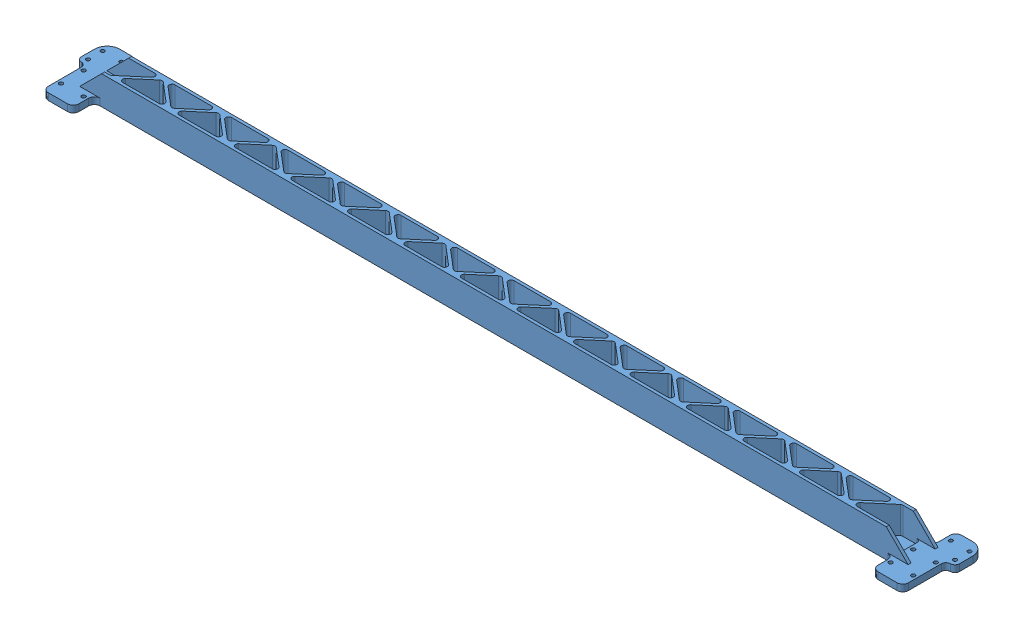
SolidWorks assembly crossbar-700-10, configuration Aluminum Crossbar. Lengths in mm.
Overall size (777 25.4 65).
5 component instances, 2 part files, 8 mates.
Components (placement in the parent):
- m4_composite_insert_93918A102-1: m4_composite_insert_93918A102 [93918A102] at (-74.929 387.0105 24.0665) x (-0.969139 0 0.246516) z (-0.246516 0 -0.969139) (suppressed, hidden)
- m4_composite_insert_93918A102-2: m4_composite_insert_93918A102 [93918A102] at (-91.429 387.0105 36.8915) x (-0.293941 0 0.955824) z (-0.955824 0 -0.293941) (suppressed, hidden)
- m4_composite_insert_93918A102-3: m4_composite_insert_93918A102 [93918A102] at (370.571 387.0105 36.8915) x (0.866033 0 0.499986) z (-0.499986 0 0.866033) (suppressed, hidden)
- m4_composite_insert_93918A102-4: m4_composite_insert_93918A102 [93918A102] at (354.071 387.0105 24.0665) x (-0.759413 0 -0.650609) z (0.650609 0 -0.759413) (suppressed, hidden)
- crossbar_6mm_for_700mm_mgn12_rail-2: crossbar_6mm_for_700mm_mgn12_rail [Pocketed Crossbar] at (139.571 387.0105 61.3165) size (777 25.4 65)
Mates (geometry in assembly coordinates):
- Coincident1594070444: coincident aligned: plane of crossbar_6mm_for_400mm_mgn12_rail-1 through (139.571 393.0105 61.3165) normal (0 1 0); plane of m4_composite_insert_93918A102-1 through (-72.9908 393.0105 23.5734) normal (0 1 0)
- Concentric754009872: concentric aligned: cylinder of crossbar_6mm_for_400mm_mgn12_rail-1 through (-74.929 393.0105 24.0665) axis (0 -1 0) radius 5.9875; cylinder of m4_composite_insert_93918A102-1 through (-74.929 387.0105 24.0665) axis (0 -1 0) radius 6
- Coincident1594070445: coincident aligned: plane of crossbar_6mm_for_400mm_mgn12_rail-1 through (139.571 393.0105 61.3165) normal (0 1 0); plane of m4_composite_insert_93918A102-2 through (-90.8412 393.0105 34.9798) normal (0 1 0)
- Concentric754009873: concentric anti-aligned: circle of crossbar_6mm_for_400mm_mgn12_rail-1; circle of m4_composite_insert_93918A102-2
- Coincident1594070447: coincident aligned: plane of crossbar_6mm_for_400mm_mgn12_rail-1 through (139.571 393.0105 61.3165) normal (0 1 0); plane of m4_composite_insert_93918A102-3 through (368.8389 393.0105 35.8915) normal (0 1 0)
- Coincident1594070448: coincident aligned: plane of crossbar_6mm_for_400mm_mgn12_rail-1 through (139.571 393.0105 61.3165) normal (0 1 0); plane of m4_composite_insert_93918A102-4 through (355.5898 393.0105 25.3677) normal (0 1 0)
- Concentric754009876: concentric aligned: cylinder of crossbar_6mm_for_400mm_mgn12_rail-1 through (354.071 393.0105 24.0665) axis (0 -1 0) radius 5.9875; circle of m4_composite_insert_93918A102-4
- Concentric754010077: concentric aligned: cylinder of crossbar_6mm_for_400mm_mgn12_rail-1 through (370.571 393.0105 36.8915) axis (0 -1 0) radius 5.9875; cylinder of m4_composite_insert_93918A102-3 through (370.571 387.0105 36.8915) axis (0 -1 0) radius 6
